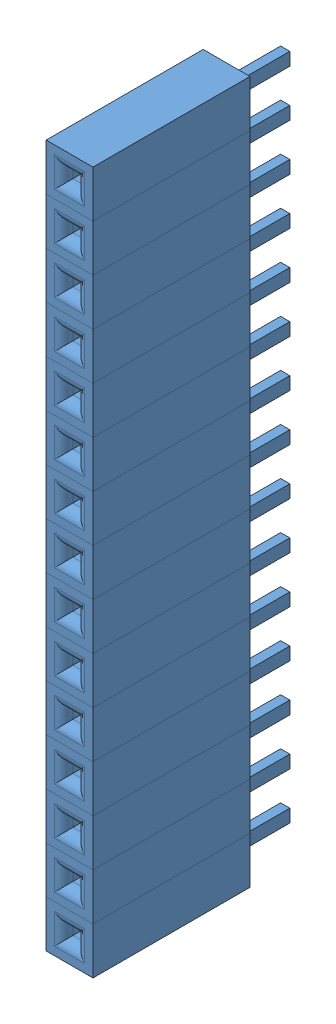
SolidWorks assembly Female Header 15 Pin, configuration Default. Lengths in mm.
Overall size (2.54 38.1 11.8).
15 component instances, 1 part files, 0 mates.
Components (placement in the parent):
- Female Header Pin-1: Female Header Pin [Default] at (-56.1039 12.7357 18.2828) size (2.54 2.54 11.8)
- Female Header Pin-2: Female Header Pin [Default] at (-56.1039 15.2757 18.2828) size (2.54 2.54 11.8)
- Female Header Pin-3: Female Header Pin [Default] at (-56.1039 17.8157 18.2828) size (2.54 2.54 11.8)
- Female Header Pin-4: Female Header Pin [Default] at (-56.1039 20.3557 18.2828) size (2.54 2.54 11.8)
- Female Header Pin-5: Female Header Pin [Default] at (-56.1039 22.8957 18.2828) size (2.54 2.54 11.8)
- Female Header Pin-6: Female Header Pin [Default] at (-56.1039 25.4357 18.2828) size (2.54 2.54 11.8)
- Female Header Pin-7: Female Header Pin [Default] at (-56.1039 27.9757 18.2828) size (2.54 2.54 11.8)
- Female Header Pin-8: Female Header Pin [Default] at (-56.1039 30.5157 18.2828) size (2.54 2.54 11.8)
- Female Header Pin-9: Female Header Pin [Default] at (-56.1039 33.0557 18.2828) size (2.54 2.54 11.8)
- Female Header Pin-10: Female Header Pin [Default] at (-56.1039 35.5957 18.2828) size (2.54 2.54 11.8)
- Female Header Pin-11: Female Header Pin [Default] at (-56.1039 38.1357 18.2828) size (2.54 2.54 11.8)
- Female Header Pin-12: Female Header Pin [Default] at (-56.1039 40.6757 18.2828) size (2.54 2.54 11.8)
- Female Header Pin-13: Female Header Pin [Default] at (-56.1039 43.2157 18.2828) size (2.54 2.54 11.8)
- Female Header Pin-14: Female Header Pin [Default] at (-56.1039 45.7557 18.2828) size (2.54 2.54 11.8)
- Female Header Pin-15: Female Header Pin [Default] at (-56.1039 48.2957 18.2828) size (2.54 2.54 11.8)
